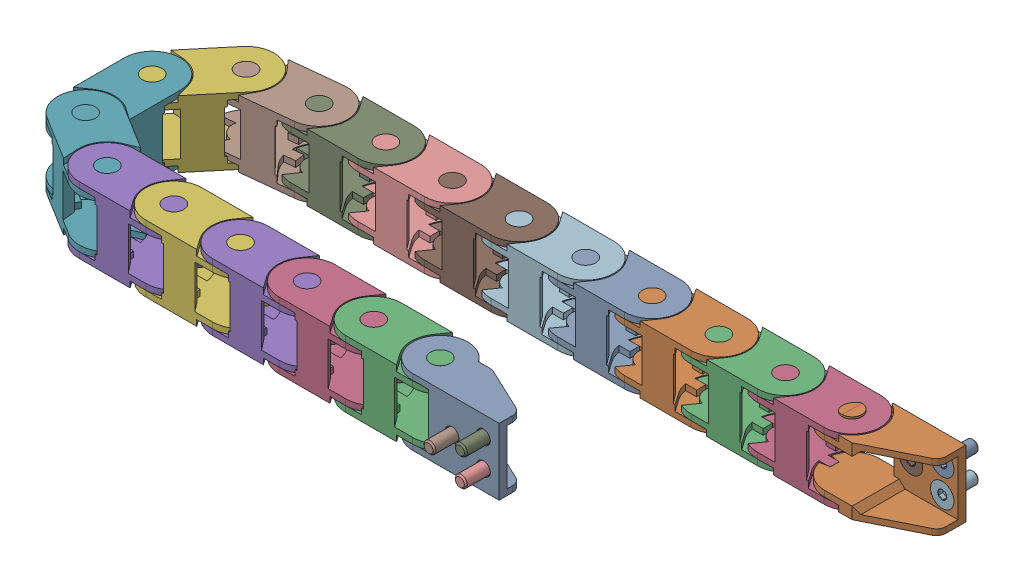
SolidWorks assembly 10x11 Chain Y, configuration Default. Lengths in mm.
Overall size (195.82 18 66.75).
25 component instances, 4 part files, 0 mates.
Components (placement in the parent):
- 10x11 Unfixed End v1 (2)-1: 10x11 Unfixed End v1 (2) [Default] at (20.785 0 38) x (-1 0 0) z (0 0 -1) size (29 17 14)
- 10x11 Fixed End v1 (2)-1: 10x11 Fixed End v1 (2) [Default] at (85.1252 17 -2.7505) x (-1 0 0) z (0 0 1) size (28.83 18 14)
- 10x11 Chain Link v1 (2)-1: 10x11 Chain Link v1 (2) [Default] at (3.785 15.5 38) size (31.2 17 14.3)
- 10x11 Chain Link v1 (2)-2: 10x11 Chain Link v1 (2) [Default] at (-13.215 15.5 38) size (31.2 17 14.3)
- 10x11 Chain Link v1 (2)-3: 10x11 Chain Link v1 (2) [Default] at (-30.215 15.5 38) size (31.2 17 14.3)
- 10x11 Chain Link v1 (2)-4: 10x11 Chain Link v1 (2) [Default] at (-47.215 15.5 38) size (31.2 17 14.3)
- 10x11 Chain Link v1 (2)-5: 10x11 Chain Link v1 (2) [Default] at (-78.6863 15.5 12.0683) x (0 0 1) z (-1 0 0) size (31.2 17 14.3)
- 10x11 Chain Link v1 (2)-6: 10x11 Chain Link v1 (2) [Default] at (-50.8748 15.5 -2.7505) x (-0.994522 0 0.104528) z (-0.104528 0 -0.994522) size (31.2 17 14.3)
- 10x11 Chain Link v1 (2)-7: 10x11 Chain Link v1 (2) [Default] at (-33.8748 15.5 -2.7505) x (-1 0 0) z (0 0 -1) size (31.2 17 14.3)
- 10x11 Chain Link v1 (2)-8: 10x11 Chain Link v1 (2) [Default] at (-16.8748 15.5 -2.7505) x (-1 0 0) z (0 0 -1) size (31.2 17 14.3)
- 10x11 Chain Link v1 (2)-9: 10x11 Chain Link v1 (2) [Default] at (0.1252 15.5 -2.7505) x (-1 0 0) z (0 0 -1) size (31.2 17 14.3)
- 10x11 Chain Link v1 (2)-10: 10x11 Chain Link v1 (2) [Default] at (17.1252 15.5 -2.7505) x (-1 0 0) z (0 0 -1) size (31.2 17 14.3)
- 10x11 Chain Link v1 (2)-11: 10x11 Chain Link v1 (2) [Default] at (34.1252 15.5 -2.7505) x (-1 0 0) z (0 0 -1) size (31.2 17 14.3)
- 10x11 Chain Link v1 (2)-12: 10x11 Chain Link v1 (2) [Default] at (51.1252 15.5 -2.7505) x (-1 0 0) z (0 0 -1) size (31.2 17 14.3)
- 10x11 Chain Link v1 (2)-13: 10x11 Chain Link v1 (2) [Default] at (68.1252 15.5 -2.7505) x (-1 0 0) z (0 0 -1) size (31.2 17 14.3)
- 10x11 Chain Link v1 (2)-14: 10x11 Chain Link v1 (2) [Default] at (85.1252 15.5 -2.7505) x (-1 0 0) z (0 0 -1) size (31.2 17 14.3)
- 10x11 Chain Link v1 (2)-15: 10x11 Chain Link v1 (2) [Default] at (-64.215 15.5 38) size (31.2 17 14.3)
- 10x11 Chain Link v1 (2)-16: 10x11 Chain Link v1 (2) [Default] at (-67.7817 15.5 -0.9735) x (-0.64145 0 0.767165) z (-0.767165 0 -0.64145) size (31.2 17 14.3)
- 10x11 Chain Link v1 (2)-17: 10x11 Chain Link v1 (2) [Default] at (-78.6788 15.5 29.067) x (0.850811 0 0.525472) z (-0.525472 0 0.850811) size (31.2 17 14.3)
- M3x8 FHCS (1) (1)-1: M3x8 FHCS (1) (1) [Default] at (30.785 8.5 43) x (-1 0 0) z (0 0 -1) size (6 6 8.12)
- M3x8 FHCS (1) (1)-2: M3x8 FHCS (1) (1) [Default] at (38.785 12 43) x (-1 0 0) z (0 0 -1) size (6 6 8.12)
- M3x8 FHCS (1) (1)-3: M3x8 FHCS (1) (1) [Default] at (38.785 5 43) x (-1 0 0) z (0 0 -1) size (6 6 8.12)
- M3x8 FHCS (1) (1)-4: M3x8 FHCS (1) (1) [Default] at (95.1252 8.5 -7.7505) x (-1 0 0) z (0 0 1) size (6 6 8.12)
- M3x8 FHCS (1) (1)-5: M3x8 FHCS (1) (1) [Default] at (103.1252 5 -7.7505) x (-1 0 0) z (0 0 1) size (6 6 8.12)
- M3x8 FHCS (1) (1)-6: M3x8 FHCS (1) (1) [Default] at (103.1252 12 -7.7505) x (-1 0 0) z (0 0 1) size (6 6 8.12)
